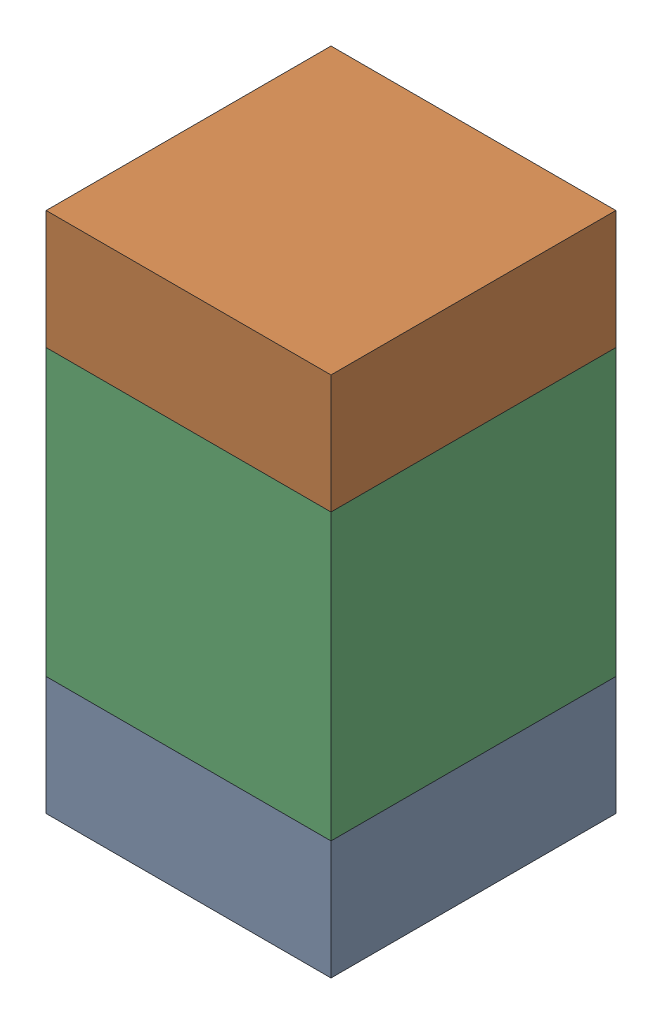
SolidWorks assembly C100_2PCB, configuration Default. Lengths in mm.
Overall size (0.6 1.1 0.6).
6 component instances, 2 part files, 0 mates.
Components (placement in the parent):
- 854785296-1: 854785296 [Default] at (107.7 99.275 0) size (0.6 0.25 0.6)
  - Extruded_10-1: Extruded_10 [Default] at origin size (0.6 0.25 0.6)
- 854785296-2: 854785296 [Default] at (107.7 100.125 0) size (0.6 0.25 0.6)
  - Extruded_10-1: Extruded_10 [Default] at origin size (0.6 0.25 0.6)
- 761606048-1: 761606048 [Default] at (107.7 99.7 0) size (0.6 0.6 0.6)
  - Extruded_9-1: Extruded_9 [Default] at origin size (0.6 0.6 0.6)
